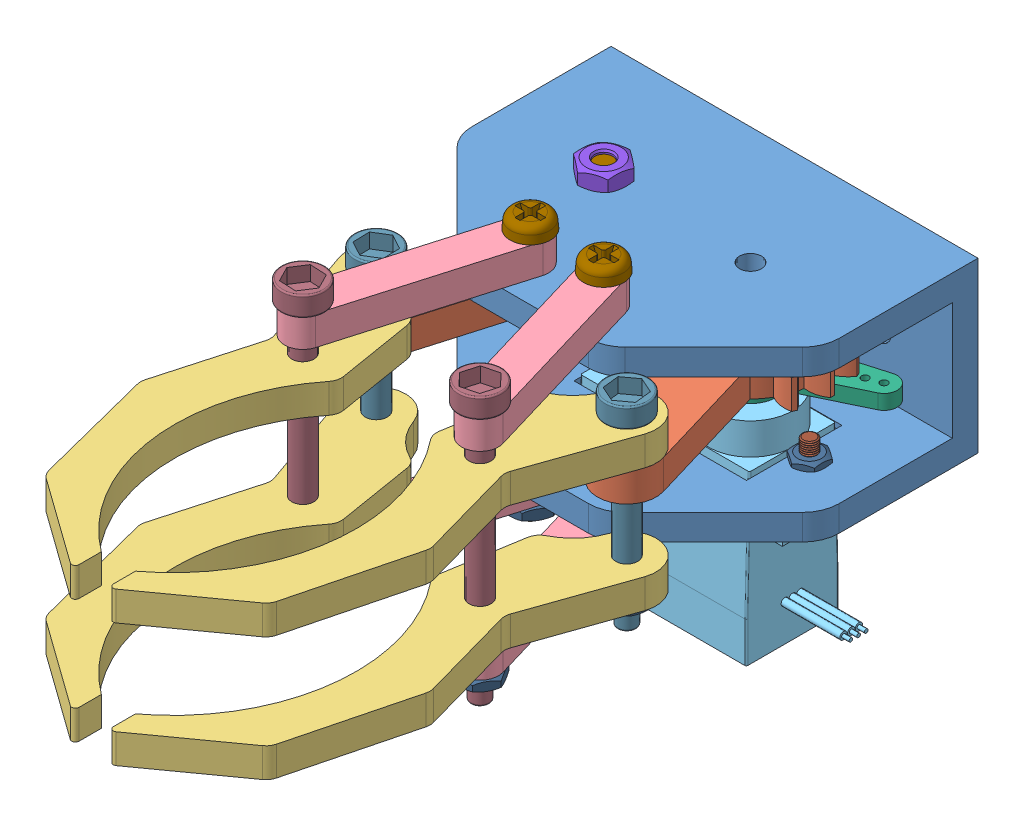
SolidWorks assembly 机械臂, configuration 默认. Lengths in mm.
Overall size (57.38 48.36 95.74).
38 component instances, 14 part files, 136 mates.
Components (placement in the parent):
- 支撑板（改）-1: 支撑板（改） [默认] at (92.699 11.5 0) x (0 0 -1) z (1 0 0) size (36 23 50)
- 齿轮传动杆-6: 齿轮传动杆 [默认] at (114.1124 -5.9575 23.5308) x (0 1 0) z (0.928234 0 0.371998) size (4 39.97 22.17)
- 齿轮传动杆-7: 齿轮传动杆 [默认] at (137.1665 -6.0175 18.8655) x (0 1 0) z (0.981948 0 -0.189151) size (4 39.97 22.17)
- 机械手爪（改）-1: 机械手爪（改） [默认] at (108.145 16.84 21.3327) x (-1 0 0) z (0 1 0) size (18.74 59.73 4)
- 机械手爪（改）-2: 机械手爪（改） [默认] at (127.3846 20.84 21.3713) x (1 0 0) z (0 -1 0) size (18.74 59.73 4)
- 连杆（改）-1: 连杆（改） [默认] at (126.2551 27 42.9835) x (-0.95868 0 0.284488) z (0 -1 0) size (5 30 4)
- 连杆（改）-2: 连杆（改） [默认] at (109.2087 23 43.0028) x (0.960226 0 0.279224) z (0 1 0) size (5 30 4)
- 连杆（改）-3: 连杆（改） [默认] at (126.2551 0 42.9835) x (0.95868 0 -0.284488) z (0 -1 0) size (5 30 4)
- 连杆（改）-4: 连杆（改） [默认] at (109.2087 0 43.0028) x (-0.960226 0 -0.279224) z (0 -1 0) size (5 30 4)
- 机械手爪（改）-3: 机械手爪（改） [默认] at (108.145 0 21.3327) x (-1 0 0) z (0 1 0) size (18.74 59.73 4)
- 机械手爪（改）-4: 机械手爪（改） [默认] at (127.3846 4 21.3713) x (1 0 0) z (0 -1 0) size (18.74 59.73 4)
- SG90-2: SG90 [Default] at (126.294 -2.32 16) x (-1 0 0) z (0 0 -1) size (36.67 29.95 12.59)
  - Tower Pro 9g Micro Servo SG90-1: Tower Pro 9g Micro Servo SG90 [Default] at origin size (36.67 29.95 12.59)
- SG90 plastic Horn-1: SG90 plastic Horn [Default] at (127.699 10.84 16) x (0.933586 0 -0.358353) z (0.358353 0 0.933586) size (19.4 4 7.07)
- plain washers--product grade c gb-2: plain washers--product grade c gb [GB_FASTENER_WASHER_SMWC 3] at (107.699 17.4 16) x (-0.69769 0 0.716399) z (0 1 0) size (7 7 0.5)
- hex nuts, style 1-grades ab gb-2: hex nuts, style 1-grades ab gb [GB_FASTENER_NUT_SNAB1 M3-N] at (107.699 23 16) x (-0.923728 0 0.383049) z (0 -1 0) size (6.35 5.5 2.4)
- cross recessed cheese head screws gb-3: cross recessed cheese head screws gb [GB_CROSS_SCREWS_TYPE2 M3X12-12  H type-C] at (107.699 10.9 16) x (0 1 0) z (0 0 1) size (14.01 5.5 5.5)
- hex thin nuts-grades ab-chamfered gb-1: hex thin nuts-grades ab-chamfered gb [GB_FASTENER_NUT_STNAB M2-N] at (135.744 3.5 16) x (0.837169 0 0.546944) z (0 -1 0) size (4.62 4 1.2)
- hex thin nuts-grades ab-chamfered gb-2: hex thin nuts-grades ab-chamfered gb [GB_FASTENER_NUT_STNAB M2-N] at (108.074 3.5 16) x (0.837169 0 0.546944) z (0 -1 0) size (4.62 4 1.2)
- cross recessed countersunk head screws gb2-3: cross recessed countersunk head screws gb2 [GB_CROSS_SCREWS_TYPE10 M2X10-8.8-H1-S] at (108.074 -3.52 16) x (0 1 0) z (0.546944 0 -0.837169) size (10 3.5 3.5)
- cross recessed countersunk head screws gb2-4: cross recessed countersunk head screws gb2 [GB_CROSS_SCREWS_TYPE10 M2X10-8.8-H1-S] at (135.744 -3.52 16) x (0 1 0) z (0 0 1) size (10 3.5 3.5)
- 2.1支撑垫片-1: 2.1支撑垫片 [默认] at (107.699 19.5 16) x (1 0 0) z (0 -1 0) size (5 5 2.1)
- hex thin nuts-grades ab-chamfered gb-3: hex thin nuts-grades ab-chamfered gb [GB_FASTENER_NUT_STNAB M2.5-N] at (129.8112 -4 54.967) x (1 0 0) z (0 1 0) size (5.77 5 1.6)
- hex thin nuts-grades ab-chamfered gb-4: hex thin nuts-grades ab-chamfered gb [GB_FASTENER_NUT_STNAB M2.5-N] at (100.7184 0 40.0057) x (0.977048 0 0.213019) z (0 1 0) size (5.77 5 1.6)
- hex thin nuts-grades ab-chamfered gb-5: hex thin nuts-grades ab-chamfered gb [GB_FASTENER_NUT_STNAB M2.5-N] at (134.8112 -1.6 39.967) x (0.933255 0 -0.359214) z (0 -1 0) size (5.77 5 1.6)
- hex thin nuts-grades ab-chamfered gb-6: hex thin nuts-grades ab-chamfered gb [GB_FASTENER_NUT_STNAB M2.5-N] at (105.7184 -4 55.0057) x (1 0 0) z (0 1 0) size (5.77 5 1.6)
- 30限位螺栓-3: 30限位螺栓 [默认] at (129.8112 29.7 54.967) x (-0.844413 0 -0.535692) z (-0.535692 0 0.844413) size (5.9 37.7 5.9)
- 30限位螺栓-4: 30限位螺栓 [默认] at (105.7184 29.7 55.0057) x (0.335228 0 -0.942137) z (-0.942137 0 -0.335228) size (5.9 37.7 5.9)
- 20限位螺栓-3: 20限位螺栓 [默认] at (134.8112 23.54 39.967) x (0.648707 0 -0.761038) z (-0.761038 0 -0.648707) size (5.9 27.7 5.9)
- 20限位螺栓-4: 20限位螺栓 [默认] at (100.7184 23.54 40.0057) x (0.708583 0 -0.705627) z (-0.705627 0 -0.708583) size (5.9 27.7 5.9)
- cross recessed cheese head screws gb-5: cross recessed cheese head screws gb [GB_CROSS_SCREWS_TYPE2 M3X10-10  H type-C] at (112.699 5.5 31) x (0 -1 0) z (0 0 1) size (12.01 5.5 5.5)
- cross recessed cheese head screws gb-6: cross recessed cheese head screws gb [GB_CROSS_SCREWS_TYPE2 M3X10-10  H type-C] at (122.699 5.5 31) x (0 -1 0) z (0 0 1) size (12.01 5.5 5.5)
- cross recessed cheese head screws gb-7: cross recessed cheese head screws gb [GB_CROSS_SCREWS_TYPE2 M3X10-10  H type-C] at (122.699 29 31) x (0 -1 0) z (0 0 1) size (12.01 5.5 5.5)
- cross recessed cheese head screws gb-8: cross recessed cheese head screws gb [GB_CROSS_SCREWS_TYPE2 M3X10-10  H type-C] at (112.699 29 31) x (0 -1 0) z (0 0 1) size (12.01 5.5 5.5)
- hex thin nuts-grades ab-chamfered gb-7: hex thin nuts-grades ab-chamfered gb [GB_FASTENER_NUT_STNAB M3-N] at (122.699 17.7 31) x (1 0 0) z (0 -1 0) size (6.35 5.5 1.8)
- hex thin nuts-grades ab-chamfered gb-9: hex thin nuts-grades ab-chamfered gb [GB_FASTENER_NUT_STNAB M3-N] at (112.699 17.7 31) x (1 0 0) z (0 -1 0) size (6.35 5.5 1.8)
- hex thin nuts-grades ab-chamfered gb-11: hex thin nuts-grades ab-chamfered gb [GB_FASTENER_NUT_STNAB M3-N] at (122.699 -5.8 31) x (1 0 0) z (0 -1 0) size (6.35 5.5 1.8)
- hex thin nuts-grades ab-chamfered gb-12: hex thin nuts-grades ab-chamfered gb [GB_FASTENER_NUT_STNAB M3-N] at (112.699 -4 31) x (1 0 0) z (0 1 0) size (6.35 5.5 1.8)
Mates (geometry in assembly coordinates):
- 重合1: coincident anti-aligned: plane of 支撑板（改）-1 through (142.699 0 0) normal (0 -1 0)
- 重合2: coincident anti-aligned: plane of 支撑板（改）-1 through (142.699 23 45) normal (0 1 0); plane of 零件2-1 through (70.0462 31.0635 138.7795) normal (0 -1 0)
- 同心1: concentric aligned: cylinder of 支撑板（改）-1 through (127.699 89.5 16) axis (0 -1 0) radius 1.5; cylinder of 零件2-1 through (70.0462 81.0636 138.7795) axis (0 -1 0) radius 1.5
- 重合3: coincident anti-aligned: plane of 支撑板（改）-1 through (142.699 23 45) normal (0 1 0); plane of 零件2-2 through (70.0462 31.0635 118.7795) normal (0 -1 0)
- 同心2: concentric anti-aligned: cylinder of 支撑板（改）-1 through (107.699 89.5 16) axis (0 -1 0) radius 1.5; cylinder of 零件2-2 through (70.0462 -14.9365 118.7795) axis (0 1 0) radius 1.5
- 重合6: coincident anti-aligned: plane of 支撑板（改）-1 through (142.699 23 45) normal (0 1 0); plane of 零件2-3 through (70.0462 31.0635 118.7795) normal (0 -1 0)
- 同心3: concentric anti-aligned: cylinder of 支撑板（改）-1 through (107.699 89.5 16) axis (0 -1 0) radius 1.5; cylinder of 零件2-3 through (70.0462 -14.9365 118.7795) axis (0 1 0) radius 1.5
- 同心7: concentric aligned: cylinder of 支撑板（改）-1 through (127.699 89.5 16) axis (0 -1 0) radius 1.5; cylinder of 齿轮传动杆-7 through (127.699 62.8401 16) axis (0 -1 0) radius 1.5
- 同心9: concentric aligned: cylinder of 支撑板（改）-1 through (107.699 89.5 16) axis (0 -1 0) radius 1.5; cylinder of 齿轮传动杆-6 through (107.699 62.9001 16) axis (0 -1 0) radius 1.5
- 重合13: coincident anti-aligned: plane of 齿轮传动杆-7 through (127.699 16.84 16) normal (0 1 0); plane of 机械手爪（改）-2 through (130.4137 16.84 72.1801) normal (0 -1 0)
- 同心11: concentric aligned: cylinder of 齿轮传动杆-6 through (100.7184 12.9 40.0057) axis (0 1 0) radius 1.5; cylinder of 机械手爪（改）-2 through (100.7184 16.84 40.0057) axis (0 1 0) radius 1.5
- 重合14: coincident anti-aligned: plane of 齿轮传动杆-7 through (127.699 16.84 16) normal (0 1 0); plane of 机械手爪（改）-1 through (105.1158 16.84 72.1414) normal (0 -1 0)
- 同心12: concentric anti-aligned: cylinder of 齿轮传动杆-7 through (134.8112 12.84 39.967) axis (0 1 0) radius 1.5; cylinder of 机械手爪（改）-1 through (134.8112 20.84 39.967) axis (0 -1 0) radius 1.5
- 同心13: concentric anti-aligned: cylinder of 机械手爪（改）-1 through (129.8112 20.84 54.967) axis (0 -1 0) radius 1.5; cylinder of 连杆（改）-1 through (129.8112 23 54.967) axis (0 1 0) radius 1.55
- 同心14: concentric anti-aligned: cylinder of 支撑板（改）-1 through (122.699 89.5 31) axis (0 -1 0) radius 1.5; cylinder of 连杆（改）-1 through (122.699 23 31) axis (0 1 0) radius 1.55
- 同心15: concentric anti-aligned: cylinder of 机械手爪（改）-2 through (105.7184 16.84 55.0057) axis (0 1 0) radius 1.5; cylinder of 连杆（改）-2 through (105.7184 27 55.0057) axis (0 -1 0) radius 1.55
- 同心16: concentric aligned: cylinder of 支撑板（改）-1 through (112.699 89.5 31) axis (0 -1 0) radius 1.5; cylinder of 连杆（改）-2 through (112.699 27 31) axis (0 -1 0) radius 1.55
- 重合17: coincident anti-aligned: plane of 连杆（改）-3 through (122.699 0 31) normal (0 1 0); plane of 机械手爪（改）-3 through (105.1158 0 72.1414) normal (0 -1 0)
- 同心19: concentric anti-aligned: cylinder of 连杆（改）-3 through (129.8112 -4 54.967) axis (0 1 0) radius 1.55; cylinder of 机械手爪（改）-3 through (129.8112 4 54.967) axis (0 -1 0) radius 1.5
- 重合20: coincident anti-aligned: plane of 连杆（改）-4 through (105.7184 0 55.0057) normal (0 1 0); plane of 机械手爪（改）-4 through (130.4137 0 72.1801) normal (0 -1 0)
- 同心24: concentric anti-aligned: cylinder of 支撑板（改）-1 through (122.699 89.5 31) axis (0 -1 0) radius 1.5; cylinder of 连杆（改）-3 through (122.699 -4 31) axis (0 1 0) radius 1.55
- 同心25: concentric anti-aligned: cylinder of 支撑板（改）-1 through (112.699 89.5 31) axis (0 -1 0) radius 1.5; cylinder of 连杆（改）-4 through (112.699 -4 31) axis (0 1 0) radius 1.55
- 同心30: concentric anti-aligned: cylinder of 机械手爪（改）-1 through (129.8112 20.84 54.967) axis (0 -1 0) radius 1.5; cylinder of 连杆-2 through (50.1174 -3 156.1886) axis (0 1 0) radius 1.5
- 同心31: concentric anti-aligned: cylinder of 机械手爪（改）-3 through (129.8112 4 54.967) axis (0 -1 0) radius 1.5; cylinder of 连杆-2 through (50.1174 -3 156.1886) axis (0 1 0) radius 1.5
- 同心32: concentric anti-aligned: cylinder of 机械手爪（改）-1 through (134.8112 20.84 39.967) axis (0 -1 0) radius 1.5; cylinder of 连杆-4 through (62.6978 0 163.3985) axis (0 1 0) radius 1.5
- 同心33: concentric anti-aligned: cylinder of 机械手爪（改）-3 through (134.8112 4 39.967) axis (0 -1 0) radius 1.5; cylinder of 连杆-4 through (62.6978 0 163.3985) axis (0 1 0) radius 1.5
- 同心34: concentric anti-aligned: cylinder of 机械手爪（改）-4 through (100.7184 0 40.0057) axis (0 1 0) radius 1.5; cylinder of 连杆-5 through (62.5628 32 94.1848) axis (0 -1 0) radius 1.5
- 同心35: concentric anti-aligned: cylinder of 机械手爪（改）-2 through (100.7184 16.84 40.0057) axis (0 1 0) radius 1.5; cylinder of 连杆-5 through (62.5628 32 94.1848) axis (0 -1 0) radius 1.5
- 同心36: concentric anti-aligned: cylinder of 机械手爪（改）-4 through (105.7184 0 55.0057) axis (0 1 0) radius 1.5; cylinder of 连杆-6 through (49.9764 29.5 101.3843) axis (0 -1 0) radius 1.5
- 同心37: concentric anti-aligned: cylinder of 机械手爪（改）-2 through (105.7184 16.84 55.0057) axis (0 1 0) radius 1.5; cylinder of 连杆-6 through (49.9764 29.5 101.3843) axis (0 -1 0) radius 1.5
- 重合22: coincident aligned: plane of 机械手爪（改）-3 through (105.1158 0 72.1414) normal (0 -1 0); plane of 连杆-4 through (62.6978 0 163.3985) normal (0 -1 0)
- 重合23: coincident aligned: plane of 连杆（改）-3 through (122.699 -4 31) normal (0 -1 0); plane of 连杆-2 through (50.1174 -3 156.1886) normal (0 -1 0)
- 重合25: coincident aligned: plane of 连杆-5 through (62.5628 0 94.1848) normal (0 -1 0); plane of 机械手爪（改）-4 through (130.4137 0 72.1801) normal (0 -1 0)
- 重合26: coincident aligned: plane of 连杆（改）-4 through (105.7184 -4 55.0057) normal (0 -1 0); plane of 连杆-6 through (49.9764 -2.5 101.3843) normal (0 -1 0)
- 同心39: concentric aligned: cylinder of 连杆（改）-4 through (105.7184 -4 55.0057) axis (0 1 0) radius 1.55; cylinder of 机械手爪（改）-4 through (105.7184 0 55.0057) axis (0 1 0) radius 1.5
- 齿轮配合3: gear = 20 : 20 mm: circle of 零件2-5; circle of 零件2-4
- 重合32: coincident anti-aligned: plane of 支撑板（改）-1 through (142.699 0 0) normal (0 -1 0); plane of SG90-2/Tower Pro 9g Micro Servo SG90-1 through (138.064 0 9.705) normal (0 1 0)
- 同心41: concentric aligned: cylinder of 支撑板（改）-1 through (108.074 10 16) axis (0 -1 0) radius 1; cylinder of SG90-2/Tower Pro 9g Micro Servo SG90-1 through (108.074 8.34 16) axis (0 -1 0) radius 0.975
- 同心42: concentric aligned: cylinder of 支撑板（改）-1 through (135.744 10 16) axis (0 -1 0) radius 1; cylinder of SG90-2/Tower Pro 9g Micro Servo SG90-1 through (135.744 8.34 16) axis (0 -1 0) radius 0.975
- 重合35: coincident anti-aligned: plane of SG90-2/Tower Pro 9g Micro Servo SG90-1 through (127.699 11.29 16) normal (0 1 0); plane of SG90 plastic Horn-1 through (128.8613 11.29 15.5539) normal (0 -1 0)
- 同心44: concentric aligned: cylinder of SG90-2/Tower Pro 9g Micro Servo SG90-1 through (127.699 7.34 16) axis (0 1 0) radius 2.3; cylinder of SG90 plastic Horn-1 through (127.699 65.84 16) axis (0 1 0) radius 2.375
- 重合42: coincident anti-aligned: plane of 支撑板（改）-1 through (142.699 19.5 45) normal (0 -1 0); plane of plain washers--product grade c gb-5 through (67.0462 25.4 138.7795) normal (0 1 0)
- 同心45: concentric anti-aligned: cylinder of 支撑板（改）-1 through (127.699 89.5 16) axis (0 -1 0) radius 1.5; cylinder of plain washers--product grade c gb-5 through (67.0462 24.9 138.7795) axis (0 1 0) radius 1.7
- 重合44: coincident anti-aligned: plane of 齿轮传动杆-7 through (127.699 16.84 16) normal (0 1 0); plane of plain washers--product grade c gb-5 through (67.0462 24.9 138.7795) normal (0 -1 0)
- 同心46: concentric anti-aligned: cylinder of 支撑板（改）-1 through (107.699 89.5 16) axis (0 -1 0) radius 1.5; cylinder of plain washers--product grade c gb-2 through (107.699 16.9 16) axis (0 1 0) radius 1.7
- 重合46: coincident anti-aligned: plane of 齿轮传动杆-6 through (107.699 16.9 16) normal (0 1 0); plane of plain washers--product grade c gb-5 through (67.0462 24.9 138.7795) normal (0 -1 0)
- 重合47: coincident anti-aligned: plane of 支撑板（改）-1 through (142.699 23 45) normal (0 1 0); plane of 连杆（改）-1 through (129.8112 23 54.967) normal (0 -1 0)
- 重合48: coincident anti-aligned: plane of 支撑板（改）-1 through (142.699 23 45) normal (0 1 0); plane of 连杆（改）-2 through (105.7184 23 55.0057) normal (0 -1 0)
- 重合49: coincident anti-aligned: plane of 齿轮传动杆-6 through (107.699 12.9 16) normal (0 -1 0); plane of cross recessed cheese head screws gb-1 through (67.0462 13.4 116.9795) normal (0 1 0)
- 同心47: concentric anti-aligned: cylinder of 支撑板（改）-1 through (107.699 89.5 16) axis (0 -1 0) radius 1.5; cylinder of cross recessed cheese head screws gb-1 through (67.0462 15.9158 118.7795) axis (0 1 0) radius 1.5
- 重合51: coincident anti-aligned: plane of 齿轮传动杆-6 through (107.699 12.9 16) normal (0 -1 0); plane of cross recessed cheese head screws gb-3 through (105.899 12.9 16) normal (0 1 0)
- 同心50: concentric anti-aligned: cylinder of 支撑板（改）-1 through (107.699 89.5 16) axis (0 -1 0) radius 1.5; cylinder of cross recessed cheese head screws gb-3 through (107.699 15.4158 16) axis (0 1 0) radius 1.5
- 重合52: coincident anti-aligned: plane of 支撑板（改）-1 through (142.699 23 45) normal (0 1 0); plane of hex nuts, style 1-grades ab gb-2 through (109.8057 23 21.0805) normal (0 -1 0)
- 同心51: concentric anti-aligned: cylinder of hex nuts, style 1-grades ab gb-2 through (107.699 25.4 16) axis (0 -1 0) radius 1.2295; cylinder of cross recessed cheese head screws gb-3 through (107.699 15.4158 16) axis (0 1 0) radius 1.5
- 重合54: coincident anti-aligned: plane of SG90-2/Tower Pro 9g Micro Servo SG90-1 through (110.394 -2.32 9.705) normal (0 -1 0); circle of cross recessed countersunk head screws gb2-2
- 同心52: concentric anti-aligned: cylinder of SG90-2/Tower Pro 9g Micro Servo SG90-1 through (108.074 8.34 16) axis (0 -1 0) radius 0.975; cylinder of cross recessed countersunk head screws gb2-2 through (67.0462 0.9958 120.5595) axis (0 1 0) radius 1
- 重合55: coincident anti-aligned: plane of SG90-2/Tower Pro 9g Micro Servo SG90-1 through (138.064 -2.32 9.705) normal (0 -1 0); circle of cross recessed countersunk head screws gb2-1
- 同心53: concentric anti-aligned: cylinder of SG90-2/Tower Pro 9g Micro Servo SG90-1 through (135.744 8.34 16) axis (0 -1 0) radius 0.975; cylinder of cross recessed countersunk head screws gb2-1 through (67.0462 0.9958 148.2295) axis (0 1 0) radius 1.75
- 重合56: coincident anti-aligned: plane of 支撑板（改）-1 through (142.699 3.5 3.5) normal (0 1 0); plane of hex thin nuts-grades ab-chamfered gb-2 through (106.2678 3.5 12.431) normal (0 -1 0)
- 同心54: concentric aligned: circle of cross recessed countersunk head screws gb2-2; cylinder of hex thin nuts-grades ab-chamfered gb-2 through (108.074 4.7 16) axis (0 -1 0) radius 0.7835
- 重合57: coincident anti-aligned: plane of SG90-2/Tower Pro 9g Micro Servo SG90-1 through (110.394 -2.32 9.705) normal (0 -1 0); circle of cross recessed countersunk head screws gb2-3
- 同心55: concentric aligned: cylinder of SG90-2/Tower Pro 9g Micro Servo SG90-1 through (108.074 8.34 16) axis (0 -1 0) radius 0.975; circle of cross recessed countersunk head screws gb2-3
- 重合58: coincident anti-aligned: plane of SG90-2/Tower Pro 9g Micro Servo SG90-1 through (138.064 -2.32 9.705) normal (0 -1 0); circle of cross recessed countersunk head screws gb2-4
- 同心56: concentric anti-aligned: cylinder of SG90-2/Tower Pro 9g Micro Servo SG90-1 through (135.744 8.34 16) axis (0 -1 0) radius 0.975; cylinder of cross recessed countersunk head screws gb2-4 through (135.744 0.9958 16) axis (0 1 0) radius 1.75
- 重合59: coincident anti-aligned: plane of 支撑板（改）-1 through (142.699 3.5 3.5) normal (0 1 0); plane of hex thin nuts-grades ab-chamfered gb-1 through (133.9378 3.5 12.431) normal (0 -1 0)
- 同心57: concentric aligned: cylinder of hex thin nuts-grades ab-chamfered gb-1 through (135.744 4.7 16) axis (0 -1 0) radius 0.7835; circle of cross recessed countersunk head screws gb2-4
- 重合61: coincident anti-aligned: plane of 齿轮传动杆-6 through (107.699 16.9 16) normal (0 1 0); plane of plain washers--product grade c gb-2 through (107.699 16.9 16) normal (0 -1 0)
- 重合63: coincident anti-aligned: plane of 齿轮传动杆-7 through (127.699 12.84 16) normal (0 -1 0); plane of SG90 plastic Horn-1 through (130.9992 12.84 14.7332) normal (0 1 0)
- 重合64: coincident anti-aligned: plane of 支撑板（改）-1 through (142.699 0 0) normal (0 -1 0); plane of 连杆（改）-4 through (105.7184 0 55.0057) normal (0 1 0)
- 重合66: coincident anti-aligned: plane of 支撑板（改）-1 through (142.699 0 0) normal (0 -1 0); plane of 连杆（改）-3 through (122.699 0 31) normal (0 1 0)
- 重合67: coincident anti-aligned: plane of 连杆（改）-3 through (122.699 -4 31) normal (0 -1 0); circle of slotted ctsk screws waisted shank gb-3
- 重合68: coincident anti-aligned: plane of 连杆（改）-1 through (129.8112 27 54.967) normal (0 1 0); plane of slotted screws with waisted shank gb-5 through (49.0811 23.9 146.4039) normal (0 -1 0)
- 重合71: coincident anti-aligned: plane of 支撑板（改）-1 through (142.699 19.5 45) normal (0 -1 0); plane of 0.1垫片-1 through (107.699 19.5 16) normal (0 1 0)
- 同心58: concentric aligned: cylinder of cross recessed cheese head screws gb-3 through (107.699 15.4158 16) axis (0 1 0) radius 1.5; cylinder of 0.1垫片-1 through (107.699 17.4 16) axis (0 1 0) radius 1.5
- 重合72: coincident anti-aligned: plane of plain washers--product grade c gb-2 through (107.699 17.4 16) normal (0 1 0); plane of 0.1垫片-1 through (107.699 17.4 16) normal (0 -1 0)
- 重合73: coincident anti-aligned: plane of 连杆（改）-3 through (122.699 -4 31) normal (0 -1 0); plane of 25限位螺栓-1 through (31.7301 -4 138.5188) normal (0 1 0)
- 同心59: concentric anti-aligned: cylinder of 连杆（改）-3 through (129.8112 -4 54.967) axis (0 1 0) radius 1.55; cylinder of 25限位螺栓-1 through (31.7301 26 138.5188) axis (0 -1 0) radius 1.5
- 同心61: concentric aligned: cylinder of 机械手爪（改）-1 through (129.8112 20.84 54.967) axis (0 -1 0) radius 1.5; cylinder of 25限位螺栓-1 through (31.7301 26 138.5188) axis (0 -1 0) radius 1.5
- 重合76: coincident anti-aligned: plane of 25限位螺栓-1 through (31.7301 26 138.5188) normal (0 1 0); plane of hex thin nuts-grades ab-chamfered gb-3 through (125.481 -5.6 57.467) normal (0 -1 0)
- 同心63: concentric anti-aligned: cylinder of 25限位螺栓-1 through (31.7301 31 138.5188) axis (0 -1 0) radius 1.25; cylinder of hex thin nuts-grades ab-chamfered gb-3 through (129.8112 -5.6 54.967) axis (0 1 0) radius 1.0065
- 重合77: coincident anti-aligned: plane of 机械手爪（改）-4 through (130.4137 0 72.1801) normal (0 -1 0); plane of 25限位螺栓1-1 through (45.1123 0 106.7836) normal (0 1 0)
- 同心64: concentric anti-aligned: cylinder of 机械手爪（改）-4 through (100.7184 0 40.0057) axis (0 1 0) radius 1.5; cylinder of 25限位螺栓1-1 through (45.1123 25 106.7836) axis (0 -1 0) radius 1.5
- 同心65: concentric anti-aligned: cylinder of 齿轮传动杆-6 through (100.7184 12.9 40.0057) axis (0 1 0) radius 1.5; cylinder of 25限位螺栓1-1 through (45.1123 25 106.7836) axis (0 -1 0) radius 1.5
- 重合78: coincident anti-aligned: plane of hex thin nuts-grades ab-chamfered gb-4 through (95.9551 -1.6 41.5259) normal (0 -1 0); plane of 25限位螺栓1-1 through (45.1123 25 106.7836) normal (0 1 0)
- 同心66: concentric aligned: circle of hex thin nuts-grades ab-chamfered gb-4; cylinder of 25限位螺栓1-1 through (45.1123 30 106.7836) axis (0 -1 0) radius 1.25
- 同心67: concentric anti-aligned: cylinder of 连杆（改）-4 through (105.7184 -4 55.0057) axis (0 1 0) radius 1.55; cylinder of 25限位螺栓-2 through (31.7089 55 119.2025) axis (0 -1 0) radius 1.5
- 重合80: coincident anti-aligned: plane of hex thin nuts-grades ab-chamfered gb-6 through (101.3882 -5.6 57.5057) normal (0 -1 0); plane of 25限位螺栓-2 through (31.7089 55 119.2025) normal (0 1 0)
- 同心68: concentric anti-aligned: cylinder of hex thin nuts-grades ab-chamfered gb-6 through (105.7184 -5.6 55.0057) axis (0 1 0) radius 1.0065; cylinder of 25限位螺栓-2 through (31.7089 60 119.2025) axis (0 -1 0) radius 1.25
- 重合81: coincident anti-aligned: plane of 机械手爪（改）-3 through (105.1158 0 72.1414) normal (0 -1 0); plane of 25限位螺栓1-2 through (43.4542 0 147.0508) normal (0 1 0)
- 同心69: concentric aligned: cylinder of 机械手爪（改）-3 through (134.8112 4 39.967) axis (0 -1 0) radius 1.5; cylinder of 25限位螺栓1-2 through (43.4542 25 147.0508) axis (0 -1 0) radius 1.5
- 重合82: coincident anti-aligned: plane of hex thin nuts-grades ab-chamfered gb-5 through (129.872 -1.6 39.1893) normal (0 -1 0); plane of 25限位螺栓1-2 through (43.4542 25 147.0508) normal (0 1 0)
- 同心70: concentric aligned: cylinder of hex thin nuts-grades ab-chamfered gb-5 through (134.8112 0 39.967) axis (0 -1 0) radius 1.0065; cylinder of 25限位螺栓1-2 through (43.4542 30 147.0508) axis (0 -1 0) radius 1.25
- 同心71: concentric anti-aligned: cylinder of 齿轮传动杆-7 through (134.8112 12.84 39.967) axis (0 1 0) radius 1.5; cylinder of 25限位螺栓1-2 through (43.4542 25 147.0508) axis (0 -1 0) radius 1.5
- 重合83: coincident aligned: plane of 连杆（改）-2 through (105.7184 27 55.0057) normal (0 1 0); plane of 25限位螺栓-2 through (31.7089 25 119.2025) normal (0 1 0)
- 重合84: coincident anti-aligned: plane of 机械手爪（改）-1 through (105.1158 20.84 72.1414) normal (0 1 0); plane of 25限位螺栓1-3 through (134.8112 20.84 39.967) normal (0 -1 0)
- 同心72: concentric anti-aligned: cylinder of 机械手爪（改）-1 through (134.8112 20.84 39.967) axis (0 -1 0) radius 1.5; cylinder of 25限位螺栓1-3 through (134.8112 0.84 39.967) axis (0 1 0) radius 1.5
- 同心73: concentric anti-aligned: cylinder of 机械手爪（改）-3 through (134.8112 4 39.967) axis (0 -1 0) radius 1.5; cylinder of 25限位螺栓1-3 through (134.8112 0.84 39.967) axis (0 1 0) radius 1.5
- 同心74: concentric anti-aligned: cylinder of hex thin nuts-grades ab-chamfered gb-5 through (134.8112 0 39.967) axis (0 -1 0) radius 1.0065; cylinder of 25限位螺栓1-3 through (134.8112 -4.16 39.967) axis (0 1 0) radius 1.25
- 重合86: coincident anti-aligned: plane of 连杆（改）-1 through (129.8112 27 54.967) normal (0 1 0); plane of 25限位螺栓-3 through (129.8112 27 54.967) normal (0 -1 0)
- 同心75: concentric aligned: cylinder of 连杆（改）-1 through (129.8112 23 54.967) axis (0 1 0) radius 1.55; cylinder of 25限位螺栓-3 through (129.8112 -3 54.967) axis (0 1 0) radius 1.5
- 重合87: coincident anti-aligned: plane of hex thin nuts-grades ab-chamfered gb-3 through (125.481 -4 57.467) normal (0 1 0); plane of 连杆（改）-3 through (122.699 -4 31) normal (0 -1 0)
- 同心76: concentric aligned: cylinder of hex thin nuts-grades ab-chamfered gb-3 through (129.8112 -5.6 54.967) axis (0 1 0) radius 1.0065; cylinder of 25限位螺栓-3 through (129.8112 -8 54.967) axis (0 1 0) radius 1.25
- 重合88: coincident anti-aligned: plane of 连杆（改）-2 through (105.7184 27 55.0057) normal (0 1 0); plane of 25限位螺栓-4 through (105.7184 27 55.0057) normal (0 -1 0)
- 同心77: concentric anti-aligned: cylinder of 连杆（改）-2 through (105.7184 27 55.0057) axis (0 -1 0) radius 1.55; cylinder of 25限位螺栓-4 through (105.7184 -3 55.0057) axis (0 1 0) radius 1.5
- 同心79: concentric aligned: cylinder of 连杆（改）-4 through (105.7184 -4 55.0057) axis (0 1 0) radius 1.55; cylinder of 25限位螺栓-4 through (105.7184 -3 55.0057) axis (0 1 0) radius 1.5
- 重合90: coincident anti-aligned: plane of hex thin nuts-grades ab-chamfered gb-6 through (101.3882 -4 57.5057) normal (0 1 0); plane of 连杆（改）-4 through (105.7184 -4 55.0057) normal (0 -1 0)
- 同心80: concentric aligned: cylinder of hex thin nuts-grades ab-chamfered gb-6 through (105.7184 -5.6 55.0057) axis (0 1 0) radius 1.0065; cylinder of 25限位螺栓-4 through (105.7184 -8 55.0057) axis (0 1 0) radius 1.25
- 重合91: coincident anti-aligned: plane of 机械手爪（改）-2 through (130.4137 20.84 72.1801) normal (0 1 0); plane of 25限位螺栓1-4 through (100.7184 20.84 40.0057) normal (0 -1 0)
- 同心81: concentric aligned: cylinder of 机械手爪（改）-2 through (100.7184 16.84 40.0057) axis (0 1 0) radius 1.5; cylinder of 25限位螺栓1-4 through (100.7184 0.84 40.0057) axis (0 1 0) radius 1.5
- 同心82: concentric aligned: cylinder of 机械手爪（改）-4 through (100.7184 0 40.0057) axis (0 1 0) radius 1.5; cylinder of 25限位螺栓1-4 through (100.7184 0.84 40.0057) axis (0 1 0) radius 1.5
- 同心83: concentric aligned: cylinder of hex thin nuts-grades ab-chamfered gb-4 through (100.7184 -1.6 40.0057) axis (0 1 0) radius 1.0065; cylinder of 25限位螺栓1-4 through (100.7184 -4.16 40.0057) axis (0 1 0) radius 1.25
- 同心84: concentric anti-aligned: cylinder of 机械手爪（改）-3 through (129.8112 4 54.967) axis (0 -1 0) radius 1.5; cylinder of 25限位螺栓-3 through (129.8112 -3 54.967) axis (0 1 0) radius 1.5
- 重合93: coincident anti-aligned: plane of 连杆（改）-1 through (129.8112 27 54.967) normal (0 1 0); plane of cross recessed cheese head screws gb-7 through (124.499 27 31) normal (0 -1 0)
- 同心85: concentric anti-aligned: cylinder of 连杆（改）-1 through (122.699 23 31) axis (0 1 0) radius 1.55; cylinder of cross recessed cheese head screws gb-7 through (122.699 24.4842 31) axis (0 -1 0) radius 1.5
- 重合94: coincident anti-aligned: plane of 连杆（改）-2 through (105.7184 27 55.0057) normal (0 1 0); plane of cross recessed cheese head screws gb-8 through (114.499 27 31) normal (0 -1 0)
- 同心86: concentric aligned: cylinder of 连杆（改）-2 through (112.699 27 31) axis (0 -1 0) radius 1.55; cylinder of cross recessed cheese head screws gb-8 through (112.699 24.4842 31) axis (0 -1 0) radius 1.5
- 重合95: coincident anti-aligned: plane of 支撑板（改）-1 through (142.699 3.5 3.5) normal (0 1 0); plane of cross recessed cheese head screws gb-5 through (114.499 3.5 31) normal (0 -1 0)
- 同心87: concentric aligned: cylinder of 支撑板（改）-1 through (112.699 10 31) axis (0 -1 0) radius 1.5; cylinder of cross recessed cheese head screws gb-5 through (112.699 0.9842 31) axis (0 -1 0) radius 1.5
- 重合96: coincident anti-aligned: plane of 支撑板（改）-1 through (142.699 3.5 3.5) normal (0 1 0); plane of cross recessed cheese head screws gb-6 through (124.499 3.5 31) normal (0 -1 0)
- 同心88: concentric aligned: cylinder of 支撑板（改）-1 through (122.699 10 31) axis (0 -1 0) radius 1.5; cylinder of cross recessed cheese head screws gb-6 through (122.699 0.9842 31) axis (0 -1 0) radius 1.5
- 重合97: coincident anti-aligned: plane of 连杆（改）-1 through (129.8112 23 54.967) normal (0 -1 0); plane of hex thin nuts-grades ab-chamfered gb-8 through (49.3097 21 139.0947) normal (0 1 0)
- 同心89: concentric aligned: cylinder of 机械手爪-1 through (24.7049 20.84 116.6046) axis (0 -1 0) radius 23; cone of hex thin nuts-grades ab-chamfered gb-10 through (26.0265 16.84 126.2247) axis (0 -1 0)
- 重合98: coincident anti-aligned: plane of 机械手爪（改）-1 through (105.1158 16.84 72.1414) normal (0 -1 0); plane of hex thin nuts-grades ab-chamfered gb-10 through (26.0538 16.84 129.4) normal (0 1 0)
- 重合99: coincident anti-aligned: plane of 支撑板（改）-1 through (142.699 19.5 45) normal (0 -1 0); plane of hex thin nuts-grades ab-chamfered gb-7 through (117.9358 19.5 28.25) normal (0 1 0)
- 同心90: concentric aligned: cylinder of cross recessed cheese head screws gb-7 through (122.699 24.4842 31) axis (0 -1 0) radius 1.5; cylinder of hex thin nuts-grades ab-chamfered gb-7 through (122.699 19.5 31) axis (0 -1 0) radius 1.2295
- 重合103: coincident anti-aligned: plane of 支撑板（改）-1 through (142.699 19.5 45) normal (0 -1 0); plane of hex thin nuts-grades ab-chamfered gb-9 through (107.9358 19.5 28.25) normal (0 1 0)
- 同心91: concentric aligned: cylinder of cross recessed cheese head screws gb-8 through (112.699 24.4842 31) axis (0 -1 0) radius 1.5; cylinder of hex thin nuts-grades ab-chamfered gb-9 through (112.699 19.5 31) axis (0 -1 0) radius 1.2295
- 重合105: coincident anti-aligned: plane of 连杆（改）-4 through (105.7184 -4 55.0057) normal (0 -1 0); plane of hex thin nuts-grades ab-chamfered gb-12 through (107.9358 -4 33.75) normal (0 1 0)
- 同心92: concentric anti-aligned: cylinder of cross recessed cheese head screws gb-5 through (112.699 0.9842 31) axis (0 -1 0) radius 1.5; cylinder of hex thin nuts-grades ab-chamfered gb-12 through (112.699 -5.8 31) axis (0 1 0) radius 1.2295
- 重合106: coincident anti-aligned: plane of 连杆（改）-3 through (122.699 -4 31) normal (0 -1 0); plane of hex thin nuts-grades ab-chamfered gb-11 through (117.9358 -4 28.25) normal (0 1 0)
- 同心93: concentric aligned: cylinder of cross recessed cheese head screws gb-6 through (122.699 0.9842 31) axis (0 -1 0) radius 1.5; cylinder of hex thin nuts-grades ab-chamfered gb-11 through (122.699 -4 31) axis (0 -1 0) radius 1.2295
- 重合107: coincident aligned: plane of 机械手爪（改）-4 through (130.4137 0 72.1801) normal (0 -1 0); circle of hex thin nuts-grades ab-chamfered gb-4
- 重合108: coincident anti-aligned: plane of 机械手爪（改）-3 through (105.1158 0 72.1414) normal (0 -1 0); plane of hex thin nuts-grades ab-chamfered gb-5 through (129.872 0 39.1893) normal (0 1 0)
- 同心94: concentric aligned: cylinder of hex thin nuts-grades ab-chamfered gb-2 through (108.074 4.7 16) axis (0 -1 0) radius 0.7835; circle of cross recessed countersunk head screws gb2-3
- 重合109: coincident anti-aligned: plane of 支撑板（改）-1 through (142.699 23 0) normal (0 0 -1)
- 同心103: concentric anti-aligned: cylinder of 齿轮传动杆-7 through (127.699 62.8401 16) axis (0 -1 0) radius 1.5; cylinder of SG90 plastic Horn-1 through (127.699 65.84 16) axis (0 1 0) radius 1.245
